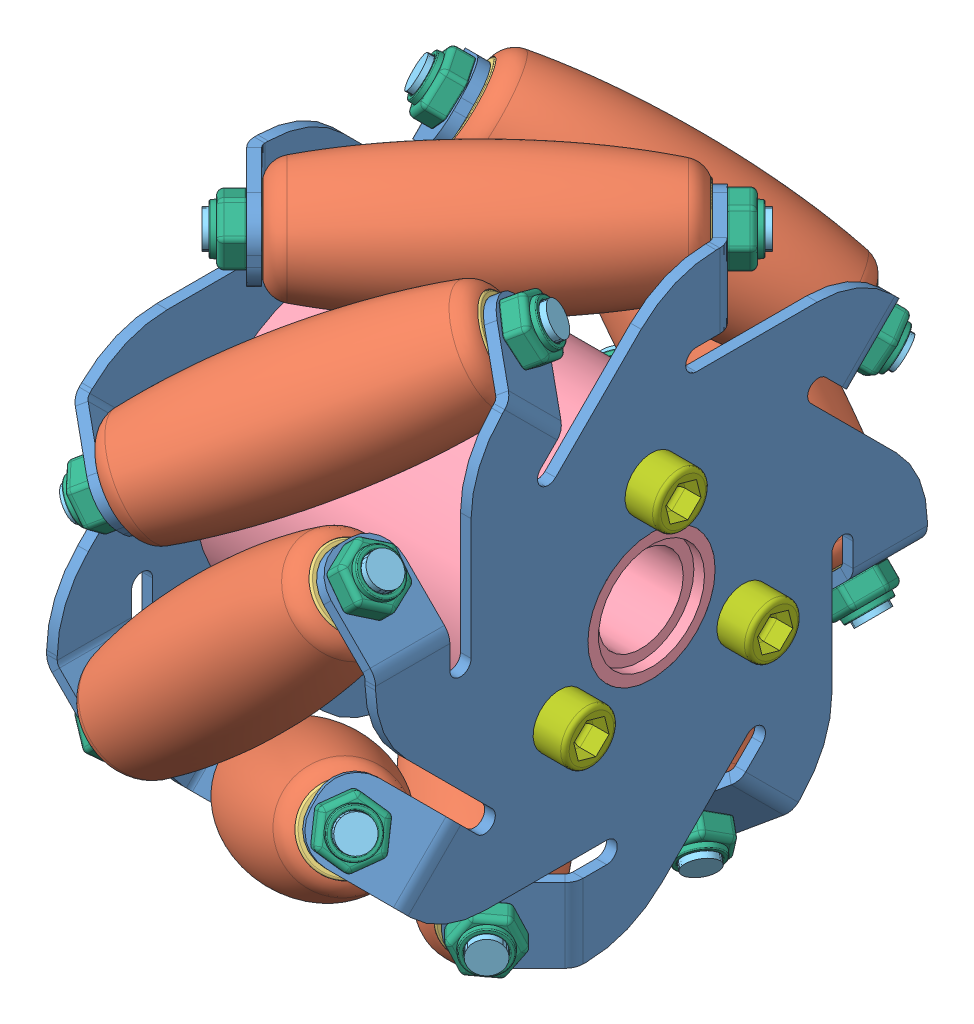
SolidWorks assembly Mecanum_Wheel_60mm_Right_ASM, configuration Varsayılan. Lengths in mm.
Overall size (83 62.09 62.09).
57 component instances, 7 part files, 17 mates.
Components (placement in the parent):
- plate_2-1: plate_2 [Varsayılan] at (56.8037 4.8798 97.2247) x (0.707107 0.707107 0) z (0 0 1) size (41.63 41.63 53.77)
- plate_2-2: plate_2 [Varsayılan] at (-25.8037 4.8798 37.0142) x (-0.707107 0.707107 0) z (0 0 -1) size (41.63 41.63 53.77)
- roller-1: roller [Varsayılan] at (15.1622 40.0059 51.0708) x (-0.707107 0.5 0.5) z (-0.704237 -0.434326 -0.561615) size (29.8 12 12)
- liner-1: liner [Varsayılan] at (4.8906 47.2689 58.3339) x (-0.663539 -0.224823 -0.713562) z (-0.24437 -0.836334 0.490743) size (7 1 7)
- liner-2: liner [Varsayılan] at (26.1038 32.2689 43.3339) x (0.54662 -0.062042 0.835079) z (-0.448561 -0.8638 0.22944) size (7 1 7)
- inner_cylinder-1: inner_cylinder [Varsayılan] at (30 23.5276 67.1195) x (0 0 1) z (-1 0 0) size (26 26 31)
- two_sided_screw-1: two_sided_screw [Varsayılan] at (28.9323 30.2689 41.3339) x (-0.195015 0.541787 -0.817579) z (-0.707107 0.5 0.5) size (3 3 38)
- 3mm_bolt-9: 3mm_bolt [Varsayılan] at (4.155 47.7891 58.854) x (0.638071 0.755922 0.146447) z (-0.707107 0.5 0.5) size (5.6 5.2 2.5)
- 3mm_bolt-10: 3mm_bolt [Varsayılan] at (26.8109 31.7689 42.8339) x (0.358192 -0.356391 0.862951) z (0.707107 -0.5 -0.5) size (5.6 5.2 2.5)
- 3x35_screw-9: 3x35_screw [Varsayılan] at (-3 18.5276 58.4592) x (0 0.745603 -0.666391) z (1 0 0) size (5 5 37)
- 3mm_bolt-25: 3mm_bolt [Varsayılan] at (0 18.5276 75.7797) x (0 -0.80734 0.590087) z (-1 0 0) size (5.6 5.2 2.5)
- 3x35_screw-12: 3x35_screw [Varsayılan] at (-3 18.5276 75.7797) x (0 -0.949913 -0.312516) z (1 0 0) size (5 5 37)
- 3x35_screw-13: 3x35_screw [Varsayılan] at (-3 33.5276 67.1195) x (0 0.20431 0.978906) z (1 0 0) size (5 5 37)
- 3mm_bolt-28: 3mm_bolt [Varsayılan] at (0 33.5276 67.1195) x (0 0.9147 0.404133) z (-1 0 0) size (5.6 5.2 2.5)
- 3mm_bolt-29: 3mm_bolt [Varsayılan] at (0 18.5276 58.4592) x (0 -0.107361 -0.99422) z (-1 0 0) size (5.6 5.2 2.5)
- two_sided_screw-9: two_sided_screw [Varsayılan] at (28.9323 10.0613 44.1195) x (-0.195015 -0.195015 -0.961217) z (-0.707107 0.707107 0) size (3 3 38)
- two_sided_screw-10: two_sided_screw [Varsayılan] at (28.9323 -2.258 60.3781) x (-0.195015 -0.817579 -0.541787) z (-0.707107 0.5 -0.5) size (3 3 38)
- two_sided_screw-11: two_sided_screw [Varsayılan] at (28.9323 0.5276 80.5857) x (-0.195015 -0.961217 0.195015) z (-0.707107 0 -0.707107) size (3 3 38)
- two_sided_screw-12: two_sided_screw [Varsayılan] at (28.9323 16.7862 92.905) x (-0.195015 -0.541787 0.817579) z (-0.707107 -0.5 -0.5) size (3 3 38)
- two_sided_screw-13: two_sided_screw [Varsayılan] at (28.9323 36.9938 90.1195) x (-0.195015 0.195015 0.961217) z (-0.707107 -0.707107 0) size (3 3 38)
- two_sided_screw-14: two_sided_screw [Varsayılan] at (28.9323 49.3131 73.8608) x (-0.195015 0.817579 0.541787) z (-0.707107 -0.5 0.5) size (3 3 38)
- two_sided_screw-15: two_sided_screw [Varsayılan] at (28.9323 46.5276 53.6532) x (-0.195015 0.961217 -0.195015) z (-0.707107 0 0.707107) size (3 3 38)
- 3mm_bolt-30: 3mm_bolt [Varsayılan] at (26.8109 12.1826 44.1195) x (0.358192 0.358192 0.862205) z (0.707107 -0.707107 0) size (5.6 5.2 2.5)
- 3mm_bolt-31: 3mm_bolt [Varsayılan] at (26.8109 -0.758 58.8781) x (0.358192 0.862951 0.356391) z (0.707107 -0.5 0.5) size (5.6 5.2 2.5)
- 3mm_bolt-32: 3mm_bolt [Varsayılan] at (26.8109 0.5276 78.4644) x (0.358192 0.862205 -0.358192) z (0.707107 0 0.707107) size (5.6 5.2 2.5)
- 3mm_bolt-33: 3mm_bolt [Varsayılan] at (26.8109 15.2862 91.405) x (0.358192 0.356391 -0.862951) z (0.707107 0.5 0.5) size (5.6 5.2 2.5)
- 3mm_bolt-34: 3mm_bolt [Varsayılan] at (26.8109 34.8725 90.1195) x (0.358192 -0.358192 -0.862205) z (0.707107 0.707107 0) size (5.6 5.2 2.5)
- 3mm_bolt-35: 3mm_bolt [Varsayılan] at (26.8109 47.8131 75.3608) x (0.358192 -0.862951 -0.356391) z (0.707107 0.5 -0.5) size (5.6 5.2 2.5)
- 3mm_bolt-36: 3mm_bolt [Varsayılan] at (26.8109 46.5276 55.7745) x (0.358192 -0.862205 0.358192) z (0.707107 0 -0.707107) size (5.6 5.2 2.5)
- 3mm_bolt-37: 3mm_bolt [Varsayılan] at (4.155 34.8385 44.1195) x (0.638071 0.638071 -0.430964) z (-0.707107 0.707107 0) size (5.6 5.2 2.5)
- 3mm_bolt-38: 3mm_bolt [Varsayılan] at (4.155 15.2622 42.858) x (0.638071 0.146447 -0.755922) z (-0.707107 0.5 -0.5) size (5.6 5.2 2.5)
- 3mm_bolt-39: 3mm_bolt [Varsayılan] at (4.155 0.5276 55.8085) x (0.638071 -0.430964 -0.638071) z (-0.707107 0 -0.707107) size (5.6 5.2 2.5)
- 3mm_bolt-40: 3mm_bolt [Varsayılan] at (4.155 -0.7339 75.3849) x (0.638071 -0.755922 -0.146447) z (-0.707107 -0.5 -0.5) size (5.6 5.2 2.5)
- 3mm_bolt-41: 3mm_bolt [Varsayılan] at (4.155 12.2166 90.1195) x (0.638071 -0.638071 0.430964) z (-0.707107 -0.707107 0) size (5.6 5.2 2.5)
- 3mm_bolt-42: 3mm_bolt [Varsayılan] at (4.155 31.793 91.381) x (0.638071 -0.146447 0.755922) z (-0.707107 -0.5 0.5) size (5.6 5.2 2.5)
- 3mm_bolt-43: 3mm_bolt [Varsayılan] at (4.155 46.5276 78.4304) x (0.638071 0.430964 0.638071) z (-0.707107 0 0.707107) size (5.6 5.2 2.5)
- liner-17: liner [Varsayılan] at (26.1038 12.8897 44.1195) x (0.54662 0.54662 0.634361) z (-0.448561 -0.448561 0.773037) size (7 1 7)
- liner-18: liner [Varsayılan] at (26.1038 -0.258 58.3781) x (0.54662 0.835079 0.062042) z (-0.448561 0.22944 0.8638) size (7 1 7)
- liner-19: liner [Varsayılan] at (26.1038 0.5276 77.7573) x (0.54662 0.634361 -0.54662) z (-0.448561 0.773037 0.448561) size (7 1 7)
- liner-20: liner [Varsayılan] at (26.1038 14.7862 90.905) x (0.54662 0.062042 -0.835079) z (-0.448561 0.8638 -0.22944) size (7 1 7)
- liner-21: liner [Varsayılan] at (26.1038 34.1654 90.1195) x (0.54662 -0.54662 -0.634361) z (-0.448561 0.448561 -0.773037) size (7 1 7)
- liner-22: liner [Varsayılan] at (26.1038 47.3131 75.8608) x (0.54662 -0.835079 -0.062042) z (-0.448561 -0.22944 -0.8638) size (7 1 7)
- liner-23: liner [Varsayılan] at (26.1038 46.5276 56.4816) x (0.54662 -0.634361 0.54662) z (-0.448561 -0.773037 -0.448561) size (7 1 7)
- liner-24: liner [Varsayılan] at (4.8906 34.1029 44.1195) x (-0.663539 -0.663539 -0.345591) z (-0.24437 -0.24437 0.938385) size (7 1 7)
- liner-25: liner [Varsayılan] at (4.8906 14.742 43.3781) x (-0.663539 -0.713562 0.224823) z (-0.24437 0.490743 0.836334) size (7 1 7)
- liner-26: liner [Varsayılan] at (4.8906 0.5276 56.5441) x (-0.663539 -0.345591 0.663539) z (-0.24437 0.938385 0.24437) size (7 1 7)
- liner-27: liner [Varsayılan] at (4.8906 -0.2138 75.905) x (-0.663539 0.224823 0.713562) z (-0.24437 0.836334 -0.490743) size (7 1 7)
- liner-28: liner [Varsayılan] at (4.8906 12.9522 90.1195) x (-0.663539 0.663539 0.345591) z (-0.24437 0.24437 -0.938385) size (7 1 7)
- liner-29: liner [Varsayılan] at (4.8906 32.3131 90.8608) x (-0.663539 0.713562 -0.224823) z (-0.24437 -0.490743 -0.836334) size (7 1 7)
- liner-30: liner [Varsayılan] at (4.8906 46.5276 77.6948) x (-0.663539 0.345591 -0.663539) z (-0.24437 -0.938385 -0.24437) size (7 1 7)
- roller-9: roller [Varsayılan] at (15.1622 23.8314 44.1195) x (-0.707107 0.707107 0) z (-0.704237 -0.704237 -0.090007) size (29.8 12 12)
- roller-10: roller [Varsayılan] at (15.1622 7.4789 50.6412) x (-0.707107 0.5 -0.5) z (-0.704237 -0.561615 0.434326) size (29.8 12 12)
- roller-11: roller [Varsayılan] at (15.1622 0.5276 66.8156) x (-0.707107 0 -0.707107) z (-0.704237 -0.090007 0.704237) size (29.8 12 12)
- roller-12: roller [Varsayılan] at (15.1622 7.0493 83.1681) x (-0.707107 -0.5 -0.5) z (-0.704237 0.434326 0.561615) size (29.8 12 12)
- roller-13: roller [Varsayılan] at (15.1622 23.2237 90.1195) x (-0.707107 -0.707107 0) z (-0.704237 0.704237 0.090007) size (29.8 12 12)
- roller-14: roller [Varsayılan] at (15.1622 39.5762 83.5977) x (-0.707107 -0.5 0.5) z (-0.704237 0.561615 -0.434326) size (29.8 12 12)
- roller-15: roller [Varsayılan] at (15.1622 46.5276 67.4233) x (-0.707107 0 0.707107) z (-0.704237 0.090007 -0.704237) size (29.8 12 12)
Mates (geometry in assembly coordinates):
- Coincident8: coincident anti-aligned: circle of plate_2-1; circle of inner_cylinder-1
- Coincident9: coincident aligned: circle of plate_2-2; circle of inner_cylinder-1
- Concentric10: concentric aligned: cylinder of plate_2-1 through (26.1038 32.2689 43.3339) axis (0.707107 -0.5 -0.5) radius 1.5; cylinder of two_sided_screw-1 through (2.0622 49.2689 60.3339) axis (0.707107 -0.5 -0.5) radius 1.5
- Parallel2: parallel anti-aligned: cylinder of plate_2-2 through (4.8962 47.3131 58.3781) axis (-0.707107 0.5 0.5) radius 1.5; cylinder of two_sided_screw-1 through (2.0622 49.2689 60.3339) axis (0.707107 -0.5 -0.5) radius 1.5
- Distance1: distance = 3 mm aligned: plane of two_sided_screw-1 through (28.9323 30.2689 41.3339) normal (0.707107 -0.5 -0.5); plane of plate_2-1 through (17.8418 14.5533 47.3652) normal (0.707107 -0.5 -0.5)
- Coincident11: coincident aligned: circle of plate_2-1; circle of 3mm_bolt-10
- Coincident14: coincident aligned: circle of plate_2-1; circle of 3x35_screw-9
- Concentric13: concentric aligned: cylinder of two_sided_screw-1 through (2.0622 49.2689 60.3339) axis (0.707107 -0.5 -0.5) radius 1.5; cylinder of 3mm_bolt-9 through (2.7408 48.7891 59.854) axis (0.707107 -0.5 -0.5) radius 1.5
- Coincident15: coincident anti-aligned: plane of plate_2-2 through (0.9382 11.641 90.4529) normal (-0.707107 0.5 0.5); plane of 3mm_bolt-9 through (3.8725 45.9809 60.2626) normal (0.707107 -0.5 -0.5)
- Coincident16: coincident anti-aligned: plane of roller-1 through (5.5977 46.7689 57.8339) normal (-0.707107 0.5 0.5); plane of liner-1 through (5.5977 46.7689 57.8339) normal (0.707107 -0.5 -0.5)
- Concentric14: concentric aligned: cylinder of roller-1 through (5.5977 46.7689 57.8339) axis (-0.707107 0.5 0.5) radius 3.5; cylinder of liner-1 through (5.5977 46.7689 57.8339) axis (-0.707107 0.5 0.5) radius 3.5
- Coincident17: coincident anti-aligned: plane of roller-1 through (25.3967 32.7689 43.8339) normal (0.707107 -0.5 -0.5); plane of liner-2 through (25.3967 32.7689 43.8339) normal (-0.707107 0.5 0.5)
- Concentric15: concentric aligned: cylinder of roller-1 through (25.3967 32.7689 43.8339) axis (0.707107 -0.5 -0.5) radius 3.5; cylinder of liner-2 through (25.3967 32.7689 43.8339) axis (0.707107 -0.5 -0.5) radius 3.5
- Coincident18: coincident aligned: circle of plate_2-2; circle of 3mm_bolt-25
- Concentric16: concentric aligned: cylinder of plate_2-2 through (1 33.5276 67.1195) axis (-1 0 0) radius 1.5; cylinder of inner_cylinder-1 through (31 33.5276 67.1195) axis (-1 0 0) radius 1.5
- Concentric17: concentric anti-aligned: cylinder of roller-1 through (26.1038 32.2689 43.3339) axis (-0.707107 0.5 0.5) radius 1.5; cylinder of two_sided_screw-1 through (2.0622 49.2689 60.3339) axis (0.707107 -0.5 -0.5) radius 1.5
- Coincident20: coincident anti-aligned: plane of plate_2-1 through (17.1347 15.0533 47.8652) normal (-0.707107 0.5 0.5); plane of liner-2 through (26.1038 32.2689 43.3339) normal (0.707107 -0.5 -0.5)
